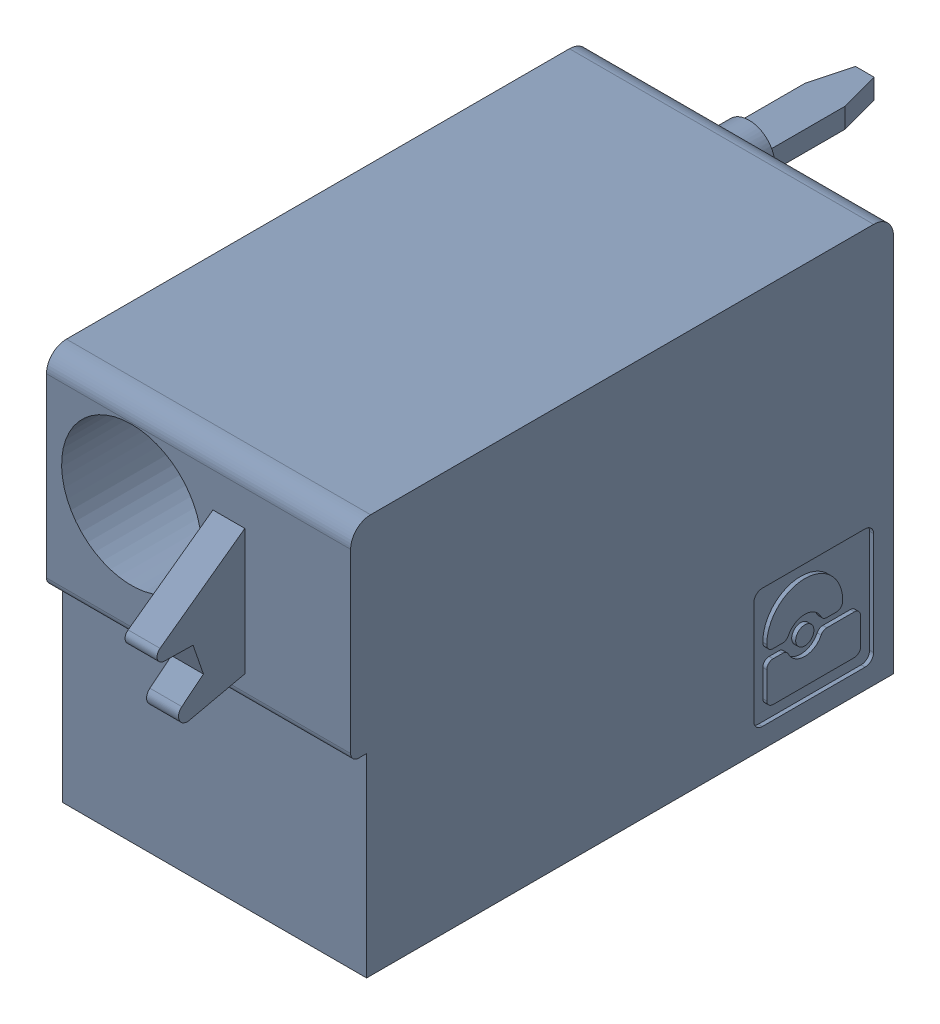
SolidWorks assembly J22, configuration Default. Lengths in mm.
Overall size (7.62 10 19.2).
2 component instances, 1 part files, 0 mates.
Components (placement in the parent):
- 1790487-1: 1790487 [Default] at (38.505 -5.67 -10.6) x (0 1 0) z (1 0 0) size (10 19.2 7.62)
  - ffkdsa1-v2-7.62-1: ffkdsa1-v2-7.62 [Default] at (-15.6914 -27.508 9.12) x (0 -1 0) z (0 0 1) size (19.2 10 7.62)
